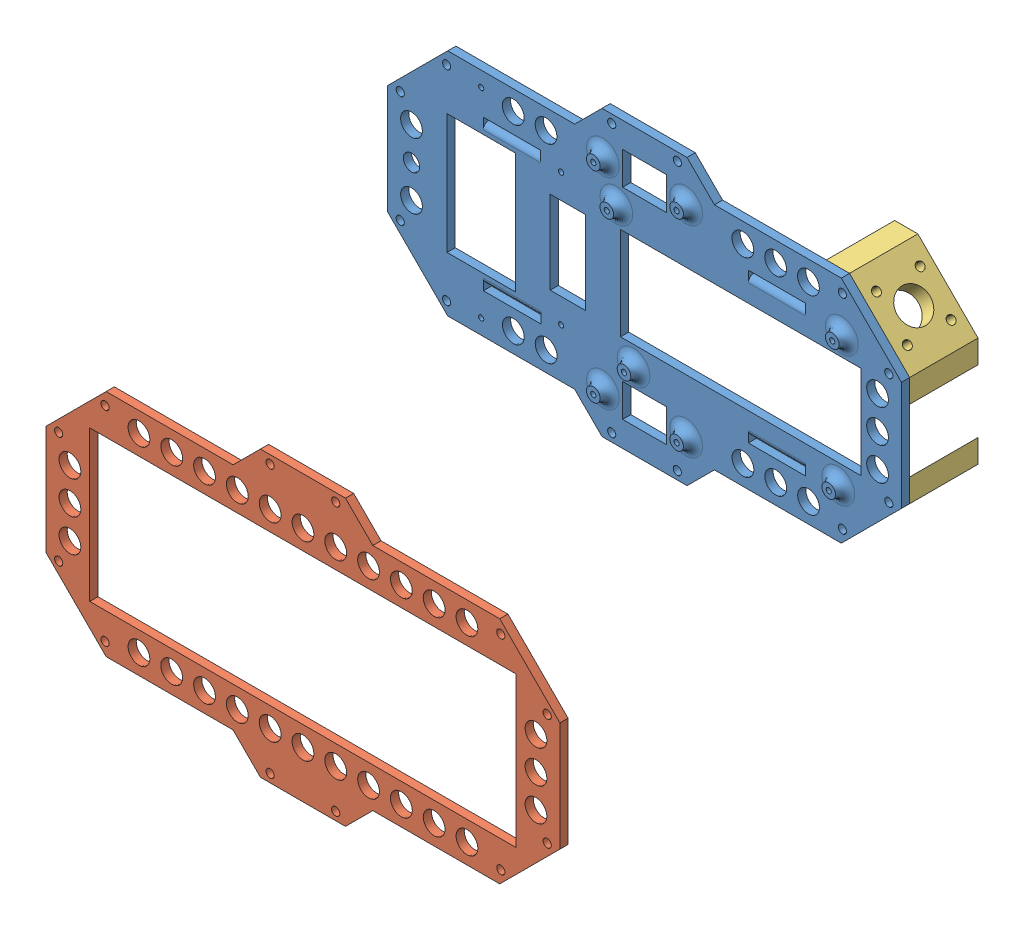
SolidWorks assembly LIUZU, configuration 默认. Lengths in mm.
Overall size (282.18 243.65 58.78).
5 component instances, 3 part files, 0 mates.
Components (placement in the parent):
- LIUZU_00-1: LIUZU_00 [默认] at origin size (282.18 243.65 58.78)
  - Assembly - Body-7-1: Assembly - Body-7 [默认] at (-8.5722 9.5723 172.25) size (188 104 6.5)
  - Assembly - Body-8-1: Assembly - Body-8 [默认] at (-102.7514 -130.0735 231.0309) size (188 104 3)
  - Assembly - Body-13-1: Assembly - Body-13 [默认] at (-8.5722 9.5723 172.25) x (-1 0 0) z (0 0 1) size (30.49 30.49 25)
  - Assembly - Body-13-2: Assembly - Body-13 [默认] at (43.4278 61.5723 172.25) x (0 1 0) z (0 0 1) size (30.49 30.49 25)
